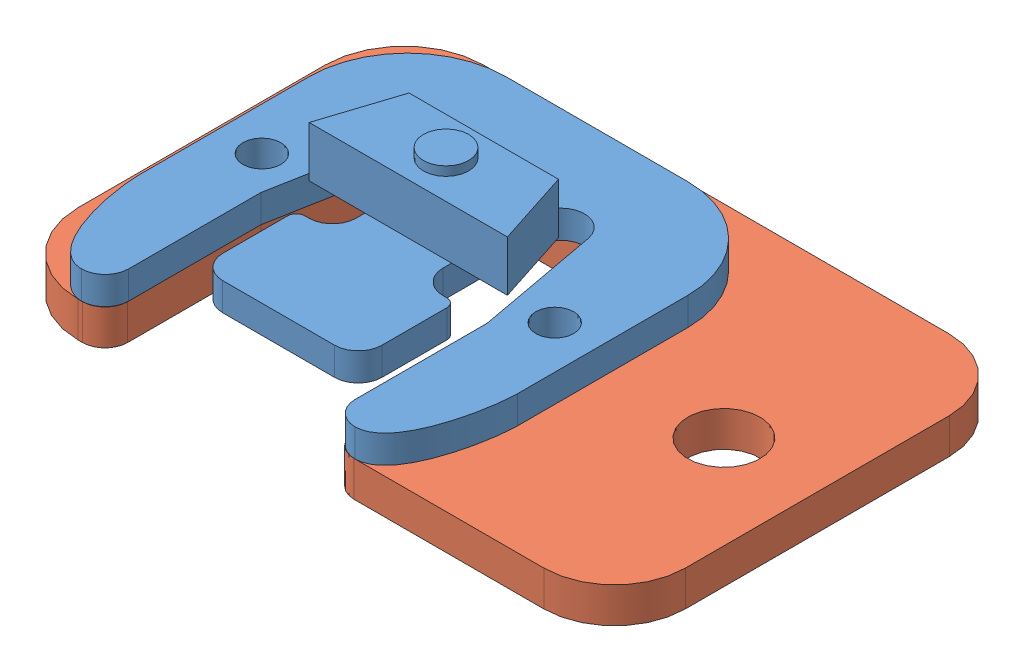
SolidWorks assembly strain-gauge-assm, configuration Default. Lengths in mm.
Overall size (65.62 11.02 53.49).
2 component instances, 2 part files, 4 mates.
Components (placement in the parent):
- strain-gauge-1: strain-gauge [Default] at (-8.7566 6.8598 -0.0397) size (33.96 8.85 33.96)
- strain-gauge.support-1: strain-gauge.support [Default] at (10.9845 3.6848 36.0625) x (-0.983384 0 0.18154) z (-0.18154 0 -0.983384) size (58.68 3.17 43.56)
Mates (geometry in assembly coordinates):
- Parallel1: parallel aligned: plane of strain-gauge-1 through (0.0572 9.3617 -0.0397) normal (0 0 -1); plane of strain-gauge.support-1 through (-4.337 6.8598 -2.44) normal (0 0 -1)
- Coincident2: coincident aligned: plane of strain-gauge-1 through (-1.924 9.3617 31.7992) normal (1 0 0); plane of strain-gauge.support-1 through (-1.924 6.8598 19.9501) normal (1 0 0)
- Coincident3: coincident anti-aligned: plane of strain-gauge-1 through (16.3894 6.8598 8.7741) normal (0 -1 0); plane of strain-gauge.support-1 through (20.4026 6.8598 31.8881) normal (0 1 0)
- Coincident4: coincident: point of strain-gauge-1; plane of strain-gauge.support-1 through (37.4206 6.8598 33.9201) normal (0 0 1)
